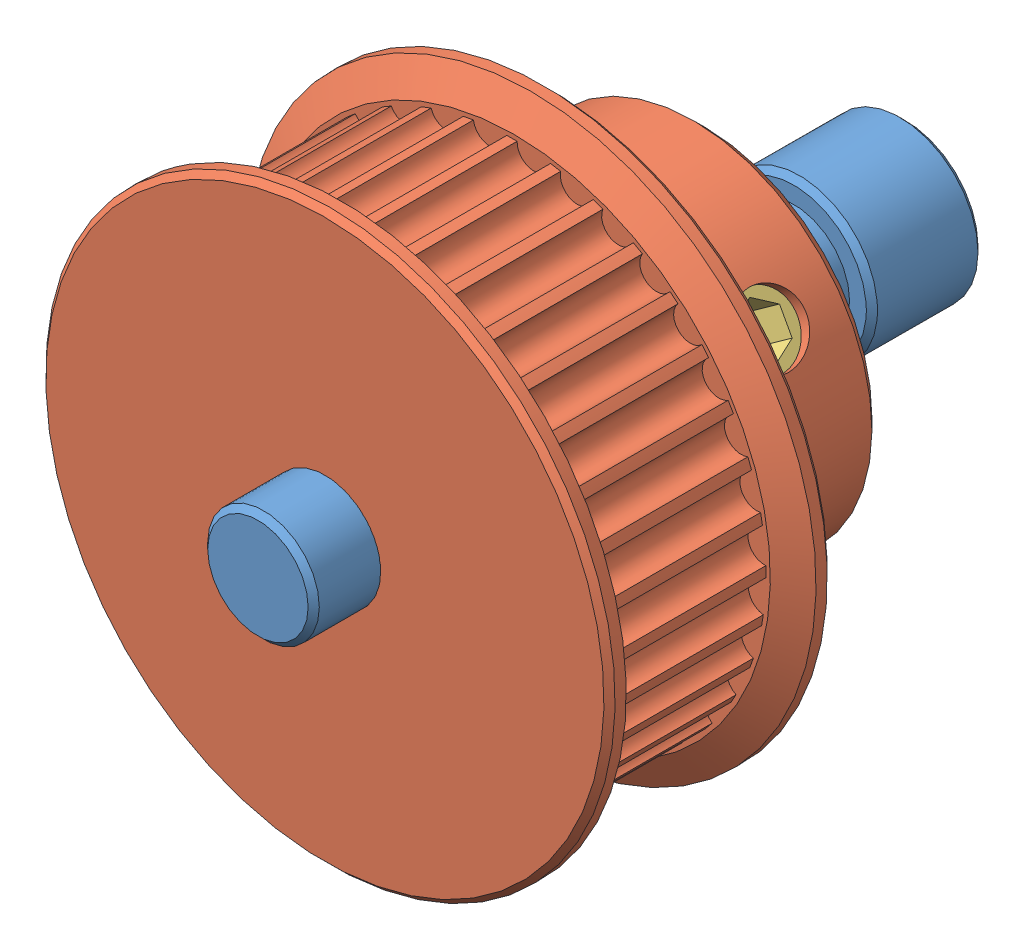
SolidWorks assembly Assieme albero e ruota condotta, configuration Default. Lengths in mm.
Overall size (35.58 35.58 29).
4 component instances, 3 part files, 6 mates.
Components (placement in the parent):
- albero per ruota condotta-1: albero per ruota condotta [Default] at (12.1553 18.5106 5.0639) size (7 7 29)
- Puleggia-1: Puleggia [Default] at (12.1553 18.5106 14.0639) x (0 0 1) z (-0.582488 0.81284 0) size (17 25.5 25.5)
- socket set screw cone point_iso-1: socket set screw cone point_iso [ISO 4027 - M4 x 5-S] at (7.7867 24.6069 17.5639) x (0.582488 -0.81284 0) z (0.403822 0.289382 -0.867863) size (5 4 4)
- socket set screw cone point_iso-2: socket set screw cone point_iso [ISO 4027 - M4 x 5-S] at (18.2516 22.8793 17.5639) x (-0.81284 -0.582488 0) z (0.245137 -0.342079 0.907133) size (5 4 4)
Mates (geometry in assembly coordinates):
- Concentrico1: concentric aligned: cylinder of albero per ruota condotta-1 through (12.1553 18.5106 34.0639) axis (0 0 -1) radius 2.5; cylinder of Puleggia-1 through (12.1553 18.5106 14.0639) axis (0 0 -1) radius 2.5
- Distanza1: distance = 3 mm aligned: plane of albero per ruota condotta-1 through (12.1553 18.5106 34.0639) normal (0 0 1); plane of Puleggia-1 through (22.519 25.9373 31.0639) normal (0 0 1)
- Concentrico2: concentric anti-aligned: cylinder of Puleggia-1 through (22.5198 25.9379 17.5639) axis (-0.81284 -0.582488 0) radius 1.5; cylinder of socket set screw cone point_iso-2 through (28.5747 30.2768 17.5639) axis (0.81284 0.582488 0) radius 2
- Coincidente1: coincident: cylinder of albero per ruota condotta-1 through (12.1553 18.5106 34.0639) axis (0 0 -1) radius 2.5; point of socket set screw cone point_iso-2
- Concentrico3: concentric anti-aligned: cylinder of Puleggia-1 through (4.728 28.8751 17.5639) axis (0.582488 -0.81284 0) radius 1.5; cylinder of socket set screw cone point_iso-1 through (0.3891 34.93 17.5639) axis (-0.582488 0.81284 0) radius 2
- Coincidente3: coincident: cylinder of albero per ruota condotta-1 through (12.1553 18.5106 34.0639) axis (0 0 -1) radius 2.5; point of socket set screw cone point_iso-1
